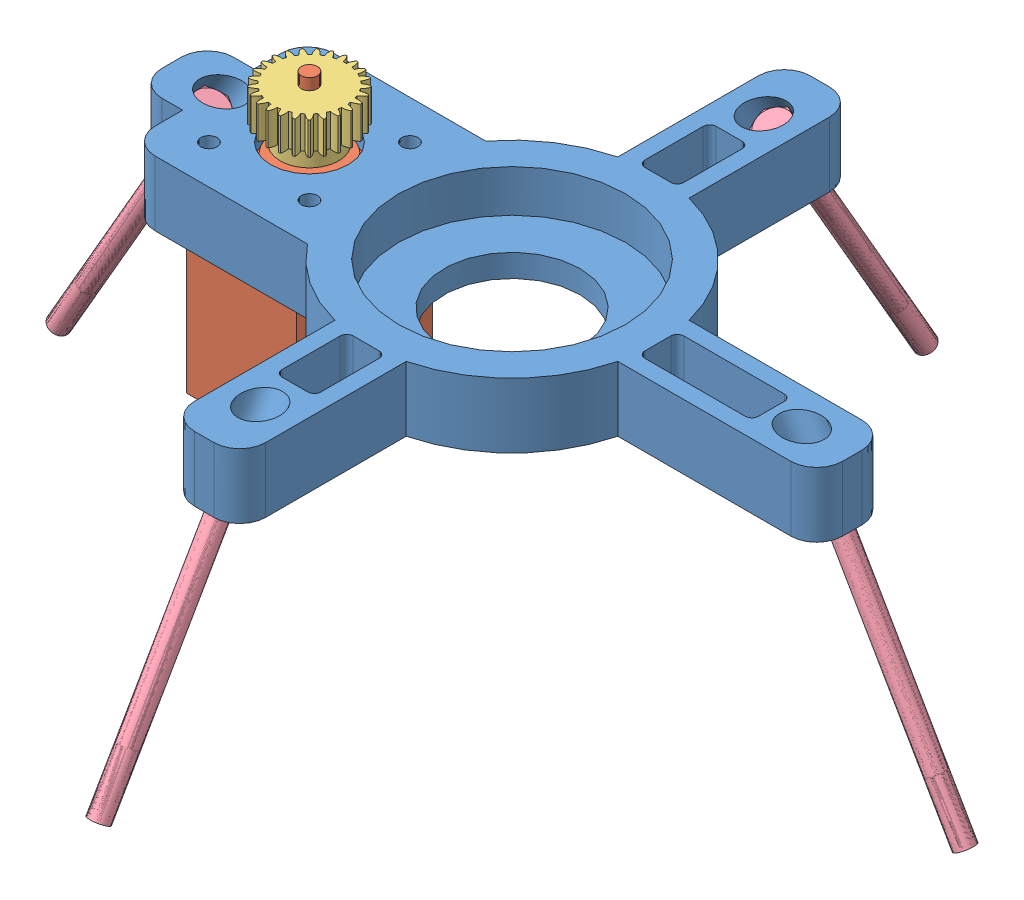
SolidWorks assembly Основание манипулятора, configuration По умолчанию. Lengths in mm.
Overall size (289.25 109.18 267.68).
7 component instances, 4 part files, 14 mates.
Components (placement in the parent):
- base-1: base [По умолчанию] at (-8.733 -19.6503 0) size (210 20 190)
- двигатель шаговый NEMA 17-1: двигатель шаговый NEMA 17 [По умолчанию] at (-71.233 -4.6503 0) x (1 0 0) z (0 -1 0) size (42 42 84)
- gear_m=1_z=25_b=10-2: gear_m=1_z=25_b=10 [DIN - Spur gear 1M 25T 20PA 10FW ---S25B18H16L5N] at (-71.233 5.8497 0) x (0 1 0) z (-0.280808 0 0.959764) size (16 26.93 26.98)
- Hex Bolt 7798_gost-12: Hex Bolt 7798_gost [Болт M6x90 ГОСТ 7798-70] at (-8.733 -4.5523 -80.5096) x (0 -0.866025 -0.5) z (0.573576 -0.409576 0.709406) size (94 11.55 10)
- Hex Bolt 7798_gost-15: Hex Bolt 7798_gost [Болт M6x90 ГОСТ 7798-70] at (-101.5417 -5.5343 0) x (-0.5 -0.866025 0) z (0.864405 -0.499064 -0.06115) size (94 11.55 10)
- Hex Bolt 7798_gost-16: Hex Bolt 7798_gost [Болт M6x90 ГОСТ 7798-70] at (84.0757 -5.5343 0) x (0.5 -0.866025 0) z (0 0 1) size (94 11.55 10)
- Hex Bolt 7798_gost-17: Hex Bolt 7798_gost [Болт M6x90 ГОСТ 7798-70] at (-8.733 -4.5523 80.5096) x (0 -0.866025 0.5) z (-0.5 0.433013 0.75) size (94 11.55 10)
Mates (geometry in assembly coordinates):
- Совпадение5: coincident aligned: plane of base-1 through (-8.733 -19.6503 0) normal (0 0 1); plane of assembly through (0 0 0) normal (0 0 1)
- Концентричный4: concentric anti-aligned: cylinder of base-1 through (-71.233 -19.6503 0) axis (0 1 0) radius 12; cylinder of двигатель шаговый NEMA 17-1 through (-71.233 19.3497 0) axis (0 -1 0) radius 2.5
- Концентричный5: concentric aligned: cylinder of base-1 through (-55.733 -19.6503 -15.5) axis (0 1 0) radius 2.5; cylinder of двигатель шаговый NEMA 17-1 through (-55.733 -4.6503 -15.5) axis (0 1 0) radius 1.25
- Совпадение7: coincident anti-aligned: plane of base-1 through (-8.733 -4.6503 0) normal (0 -1 0); plane of двигатель шаговый NEMA 17-1 through (-71.233 -4.6503 0) normal (0 1 0)
- Концентричный7: concentric anti-aligned: cylinder of двигатель шаговый NEMA 17-1 through (-71.233 19.3497 0) axis (0 -1 0) radius 2.5; cylinder of gear_m=1_z=25_b=10-2 through (-71.233 -0.1504 0) axis (0 1 0) radius 9
- Концентричный12: concentric aligned: cylinder of base-1 through (-8.733 -22.1503 -90.6699) axis (0 0.866025 0.5) radius 3.1; cylinder of Hex Bolt 7798_gost-12 through (-8.733 -4.5523 -80.5096) axis (0 0.866025 0.5) radius 3
- Совпадение12: coincident anti-aligned: plane of base-1 through (-8.733 -8.0164 -82.5096) normal (0 0.866025 0.5); plane of Hex Bolt 7798_gost-12 through (-4.0036 -6.3606 -85.3775) normal (0 -0.866025 -0.5)
- Концентричный131: concentric aligned: cylinder of base-1 through (-110.7019 -21.4003 0) axis (0.5 0.866025 0) radius 3.1; cylinder of Hex Bolt 7798_gost-15 through (-101.5417 -5.5343 0) axis (0.5 0.866025 0) radius 3
- Совпадение131: coincident anti-aligned: plane of base-1 through (-103.5417 -8.9984 0) normal (0.5 0.866025 0); plane of Hex Bolt 7798_gost-15 through (-103.8474 -8.8219 -5.7627) normal (-0.5 -0.866025 0)
- Концентричный141: concentric aligned: cylinder of base-1 through (93.2359 -21.4003 0) axis (-0.5 0.866025 0) radius 3.1; cylinder of Hex Bolt 7798_gost-16 through (84.0757 -5.5343 0) axis (-0.5 0.866025 0) radius 3
- Совпадение141: coincident anti-aligned: plane of base-1 through (86.0757 -8.9984 0) normal (-0.5 0.866025 0); plane of Hex Bolt 7798_gost-16 through (91.0757 -6.1117 0) normal (0.5 -0.866025 0)
- Концентричный151: concentric aligned: cylinder of base-1 through (-8.733 -8.0164 82.5096) axis (0 0.866025 -0.5) radius 6; cylinder of Hex Bolt 7798_gost-17 through (-8.733 -4.5523 80.5096) axis (0 0.866025 -0.5) radius 3
- Совпадение151: coincident anti-aligned: plane of base-1 through (-8.733 -8.0164 82.5096) normal (0 0.866025 -0.5); plane of Hex Bolt 7798_gost-17 through (-3.733 -6.573 85.0096) normal (0 -0.866025 0.5)
- Расстояние2: distance = 3.5 mm aligned: plane of gear_m=1_z=25_b=10-2 through (-71.233 15.8497 0) normal (0 1 0); plane of двигатель шаговый NEMA 17-1 through (-71.233 19.3497 0) normal (0 1 0)
